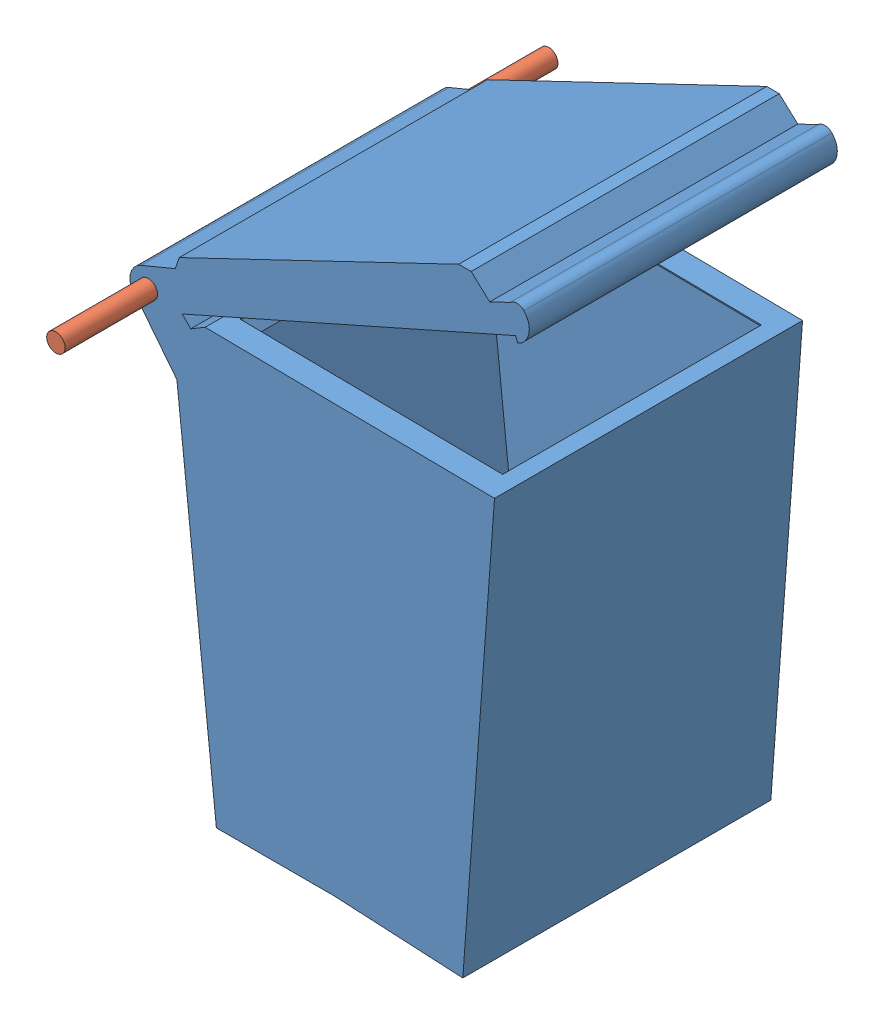
SolidWorks assembly Full Recycling Bin, configuration Default. Lengths in mm.
Overall size (8.24 12.7 10.16).
2 component instances, 2 part files, 3 mates.
Components (placement in the parent):
- Recycling Bin-1: Recycling Bin [Default] at (3.4403 3.5074 12.5542) size (8.24 12.7 6.35)
- Hook for trash can-1: Hook for trash can [Default] at (7.3321 14.2579 20.8092) x (0 0 -1) z (1 0 0) size (10.16 0.38 0.38)
Mates (geometry in assembly coordinates):
- Concentric1: concentric: cylinder of Recycling Bin-1 through (7.3321 14.2579 12.5542) axis (0 0 1) radius 0.1905; cylinder of Hook for trash can-1 through (7.3321 14.2579 20.8092) axis (0 0 -1) radius 0.1905
- Distance4: distance = 1.905 mm: plane of Hook for trash can-1 through (7.3321 14.2579 20.8092) normal (0 0 1); plane of Recycling Bin-1 through (14.7875 17.4661 18.9042) normal (0 0 1)
- Distance5: distance = 1.905 mm: plane of Recycling Bin-1 through (14.7875 17.4661 12.5542) normal (0 0 -1); plane of Hook for trash can-1 through (7.3321 14.2579 10.6492) normal (0 0 -1)
